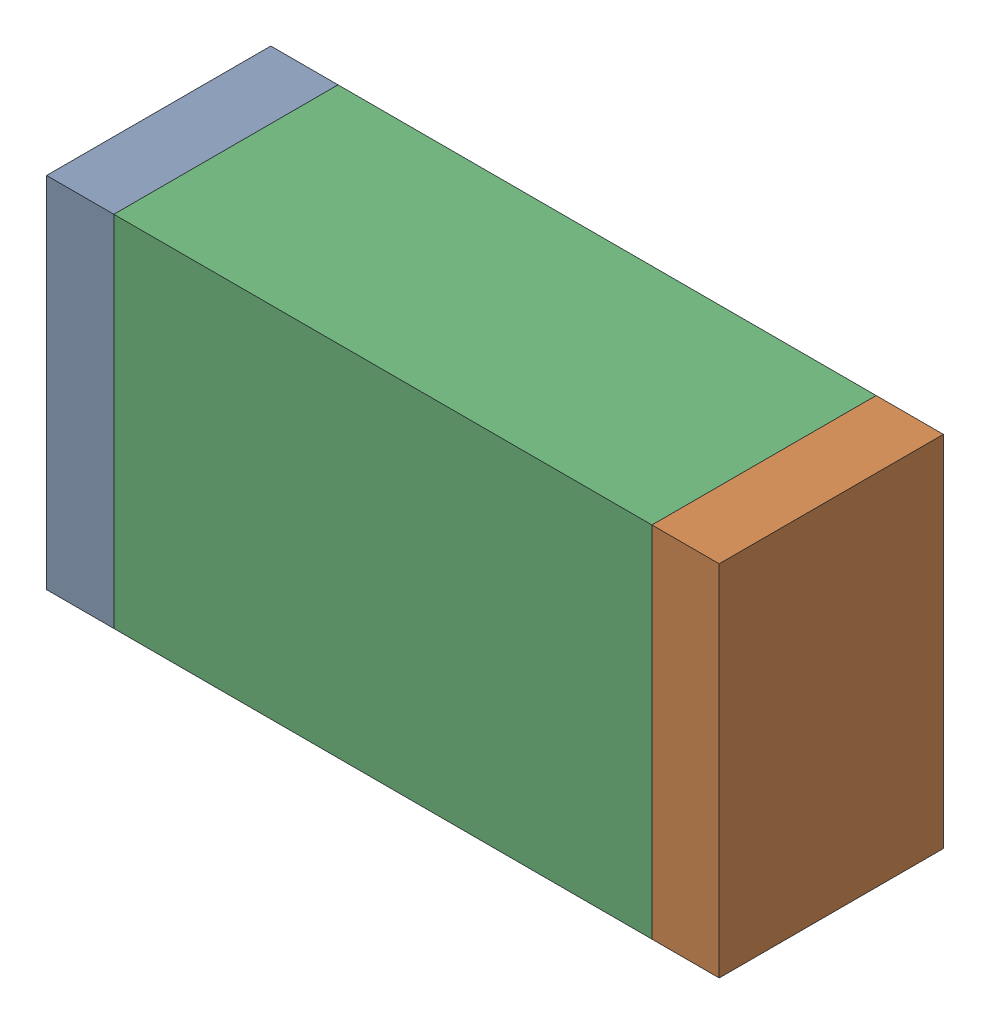
SolidWorks assembly R34, configuration Default. Lengths in mm.
Overall size (1.5 0.8 0.5).
6 component instances, 2 part files, 0 mates.
Components (placement in the parent):
- 836752496-1: 836752496 [Default] at (130.225 49.8 0) size (0.15 0.8 0.5)
  - Extruded_2-1: Extruded_2 [Default] at origin size (0.15 0.8 0.5)
- 836752496-2: 836752496 [Default] at (131.575 49.8 0) size (0.15 0.8 0.5)
  - Extruded_2-1: Extruded_2 [Default] at origin size (0.15 0.8 0.5)
- 836752368-1: 836752368 [Default] at (130.9 49.8 0) size (1.2 0.8 0.5)
  - Extruded-1: Extruded [Default] at origin size (1.2 0.8 0.5)
